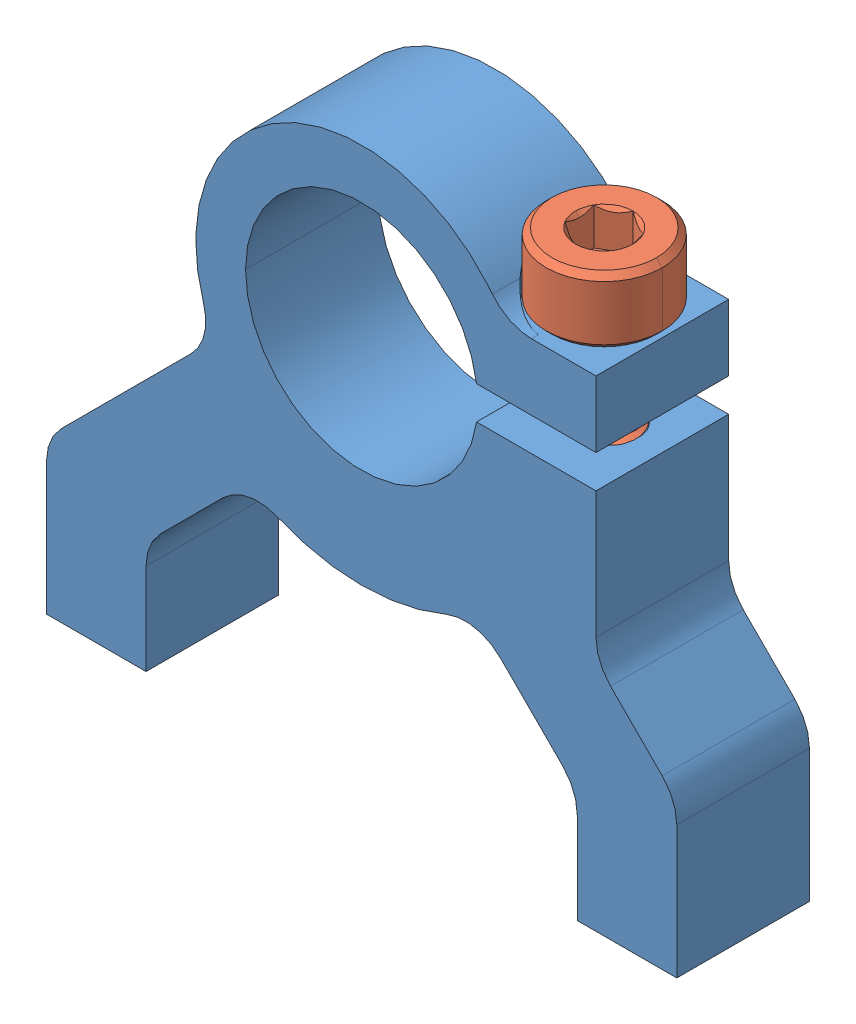
SolidWorks assembly 1400-0032-0014 assembly, configuration Default. Lengths in mm.
Overall size (38 34 8).
3 component instances, 2 part files, 0 mates.
Components (placement in the parent):
- 1400-0032-0014 assembly.STEP-1: 1400-0032-0014 assembly.STEP [Default] at origin size (38 34 8)
  - 1400-0032-0014.STEP-1: 1400-0032-0014.STEP [Default] at (-6.7355 7.0141 -0.371) size (38 34 8)
  - 2800-0004-0012_90128A207.STEP-1: 2800-0004-0012_90128A207.STEP [默认] at (3.8927 0.0141 3.629) x (1 0 0) z (0 -1 0) size (7 7 16.01)
